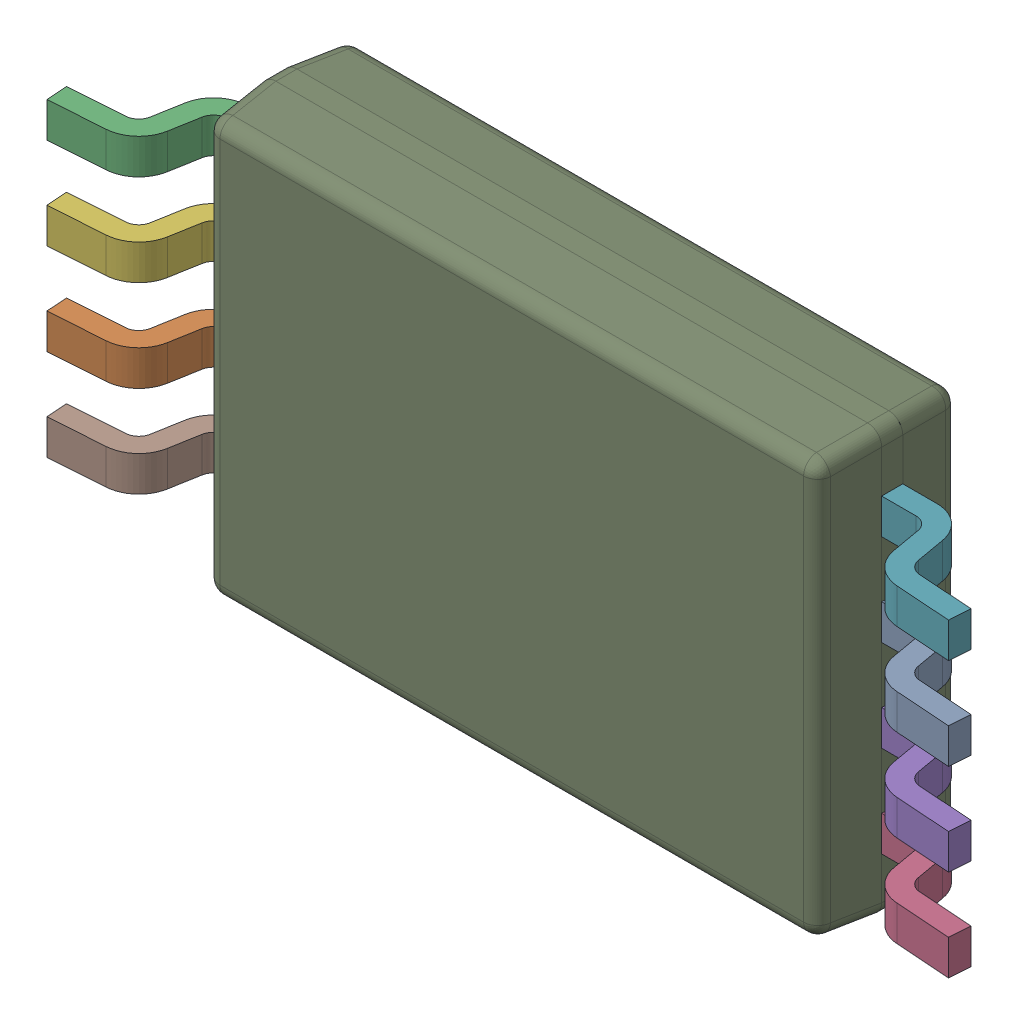
SolidWorks assembly PW0008A_ASM-1, configuration По умолчанию. Lengths in mm.
Overall size (6.42 3.01 1.1).
9 component instances, 2 part files, 0 mates.
Components (placement in the parent):
- PW0008A_ASM-Part-2-1: PW0008A_ASM-Part-2 [По умолчанию] at (2.575 0.325 -2.3511) x (0 -1 0) z (1 0 0) size (0.25 0.68 1.01)
- PW0008A_ASM-Part-2-2: PW0008A_ASM-Part-2 [По умолчанию] at (-2.575 -0.325 -2.3511) x (0 1 0) z (-1 0 0) size (0.25 0.68 1.01)
- PW0008A_ASM-Part-2-3: PW0008A_ASM-Part-2 [По умолчанию] at (-2.575 0.975 -2.3511) x (0 1 0) z (-1 0 0) size (0.25 0.68 1.01)
- PW0008A_ASM-Part-2-4: PW0008A_ASM-Part-2 [По умолчанию] at (2.575 -0.975 -2.3511) x (0 -1 0) z (1 0 0) size (0.25 0.68 1.01)
- PW0008A_ASM-Part-2-5: PW0008A_ASM-Part-2 [По умолчанию] at (2.575 -0.325 -2.3511) x (0 -1 0) z (1 0 0) size (0.25 0.68 1.01)
- PW0008A_ASM-Part-2-6: PW0008A_ASM-Part-2 [По умолчанию] at (-2.575 0.325 -2.3511) x (0 1 0) z (-1 0 0) size (0.25 0.68 1.01)
- PW0008A_ASM-Part-2-7: PW0008A_ASM-Part-2 [По умолчанию] at (2.575 0.975 -2.3511) x (0 -1 0) z (1 0 0) size (0.25 0.68 1.01)
- PW0008A_ASM-Part-2-8: PW0008A_ASM-Part-2 [По умолчанию] at (-2.575 -0.975 -2.3511) x (0 1 0) z (-1 0 0) size (0.25 0.68 1.01)
- PW0008A_ASM-Part-1-1-1: PW0008A_ASM-Part-1-1 [По умолчанию] at origin size (4.41 3.01 1)
